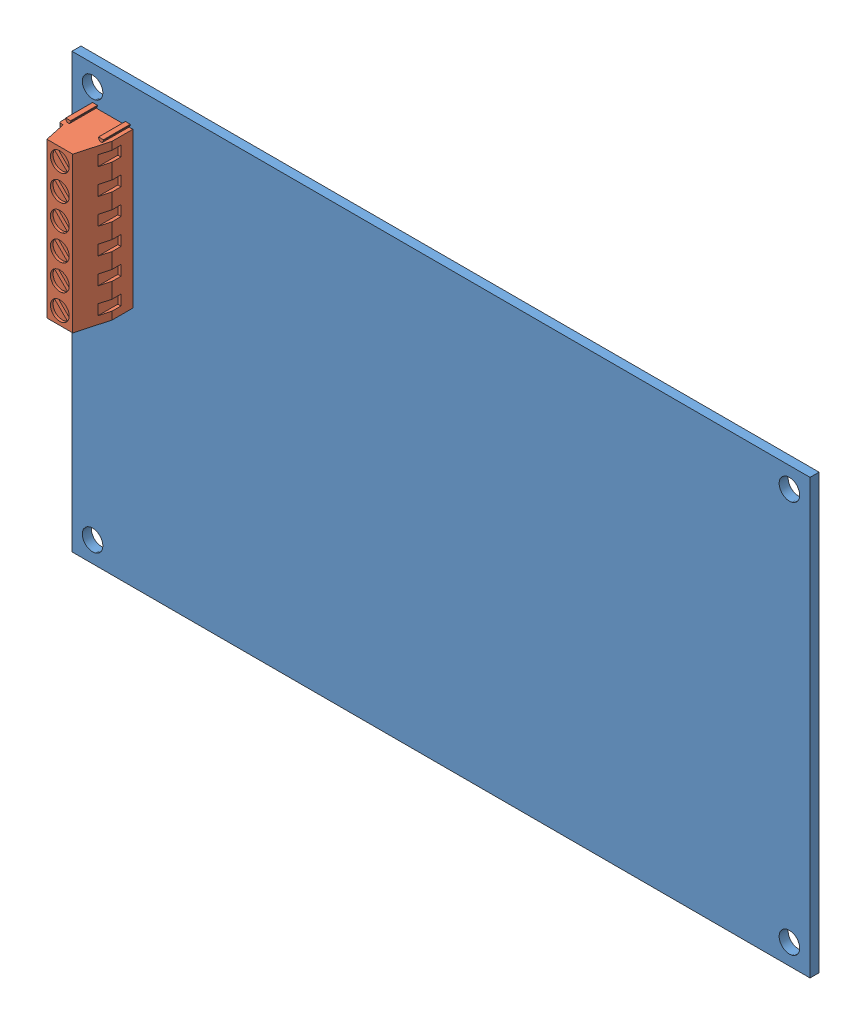
SolidWorks assembly MKS Gen V1.4 3D Printer Board v17, configuration simple. Lengths in mm.
Overall size (143 84 13.8).
45 component instances, 88 part files, 0 mates.
Components (placement in the parent):
- MKS Gen V1.4 3D Printer Board v17-1: MKS Gen V1.4 3D Printer Board v17 [Default] at origin (suppressed, hidden)
- PCB Board-1: PCB Board [Default] at origin size (143 84 1.75)
- 6 pin terminal block v1-1: 6 pin terminal block v1 [Default] at (-59.7021 19.8 1.75) x (0 -1 0) z (-1 0 0) size (30.6 13.8 8.3)
- Power terminal block v1-1: Power terminal block v1 [Default] at (-64.9521 -0.2 1.75) x (0 1 0) z (1 0 0) (suppressed, hidden)
- Power terminal block v1 (1)-1: Power terminal block v1 (1) [Default] at (-64.95 -26.8 1.75) x (0 1 0) z (1 0 0) (suppressed, hidden)
- USB socket v1-1: USB socket v1 [Default] at (-36.3816 15.6625 6.4412) x (0 1 0) z (1 0 0) (suppressed, hidden)
- Header 2_54 Vertical 2x3 v2-1: Header 2_54 Vertical 2x3 v2 [Default] at (-21.93 -38.73 1.75) x (1 0 0) z (0 -1 0) (suppressed, hidden)
- Header 2_54 Vertical 2x3 v2 (1)-1: Header 2_54 Vertical 2x3 v2 (1) [Default] at (-9.31 -38.73 1.75) x (1 0 0) z (0 -1 0) (suppressed, hidden)
- Header 2_54 Vertical 2x3 v2 (2)-1: Header 2_54 Vertical 2x3 v2 (2) [Default] at (5.21 -33.65 1.754) x (0 -1 0) z (-1 0 0) (suppressed, hidden)
- Header 2_54 Vertical 2x3 v2 (3)-1: Header 2_54 Vertical 2x3 v2 (3) [Default] at (10.29 -33.65 1.754) x (0 -1 0) z (-1 0 0) (suppressed, hidden)
- Header 2_54 Vertical 2x4 v1-1: Header 2_54 Vertical 2x4 v1 [Default] at (20.97 -38.73 1.754) x (1 0 0) z (0 -1 0) (suppressed, hidden)
- Header 2_54 Vertical 2x5 v1-1: Header 2_54 Vertical 2x5 v1 [Default] at (36.73 -38.73 1.754) x (1 0 0) z (0 -1 0) (suppressed, hidden)
- Header 2_54 Vertical 2x4 v1 (1)-1: Header 2_54 Vertical 2x4 v1 (1) [Default] at (55.13 -38.73 1.754) x (1 0 0) z (0 -1 0) (suppressed, hidden)
- 10 pin male socket v2-1: 10 pin male socket v2 [Default] at (90.0901 7.3406 1.75) x (0 1 0) z (1 0 0) (suppressed, hidden)
- 10 pin male socket v2 (1)-1: 10 pin male socket v2 (1) [Default] at (90.0901 28.9906 1.75) x (0 1 0) z (1 0 0) (suppressed, hidden)
- JST XH 3 Green v1-1: JST XH 3 Green v1 [Default] at (52.925 4.55 1.75) x (0 -1 0) z (-1 0 0) (suppressed, hidden)
- JST XH 3 Green v1 (1)-1: JST XH 3 Green v1 (1) [Default] at (46.175 4.55 1.75) x (0 -1 0) z (-1 0 0) (suppressed, hidden)
- JST XH 3 Blue v1-1: JST XH 3 Blue v1 [Default] at (39.425 4.55 1.75) x (0 -1 0) z (-1 0 0) (suppressed, hidden)
- JST XH 3 Blue v1 (1)-1: JST XH 3 Blue v1 (1) [Default] at (32.675 4.55 1.75) x (0 -1 0) z (-1 0 0) (suppressed, hidden)
- JST XH 3 Red v1-1: JST XH 3 Red v1 [Default] at (25.925 4.55 1.75) x (0 -1 0) z (-1 0 0) (suppressed, hidden)
- JST XH 3 Red v1 (1)-1: JST XH 3 Red v1 (1) [Default] at (19.175 4.55 1.75) x (0 -1 0) z (-1 0 0) (suppressed, hidden)
- JST XH 2 Black v1-1: JST XH 2 Black v1 [Default] at (52.1 -5.875 1.75) x (1 0 0) z (0 -1 0) (suppressed, hidden)
- JST XH 2 White v1-1: JST XH 2 White v1 [Default] at (52.1 -12.625 1.75) x (1 0 0) z (0 -1 0) (suppressed, hidden)
- JST XH 2 Purple v1-1: JST XH 2 Purple v1 [Default] at (52.1 -19.375 1.75) x (1 0 0) z (0 -1 0) (suppressed, hidden)
- JST XH 4 Purple v1-1: JST XH 4 Purple v1 [Default] at (57.4 37.625 1.75) x (1 0 0) z (0 -1 0) (suppressed, hidden)
- JST XH 4 Black v1-1: JST XH 4 Black v1 [Default] at (35.2 37.625 1.75) x (1 0 0) z (0 -1 0) (suppressed, hidden)
- JST XH 4 Green v1-1: JST XH 4 Green v1 [Default] at (13 37.625 1.75) x (1 0 0) z (0 -1 0) (suppressed, hidden)
- JST XH 4 Blue v1-1: JST XH 4 Blue v1 [Default] at (-9.2 37.625 1.75) x (1 0 0) z (0 -1 0) (suppressed, hidden)
- JST XH 4 Red v1-1: JST XH 4 Red v1 [Default] at (-31.4 37.625 1.75) x (1 0 0) z (0 -1 0) (suppressed, hidden)
- PIN HEADER FEMALE 8 - BLACK v4-1: PIN HEADER FEMALE 8 - BLACK v4 [Default] at (48.45 31.43 1.75) x (1 0 0) z (0 -1 0) (suppressed, hidden)
- PIN HEADER FEMALE 8 - GREEN v2-1: PIN HEADER FEMALE 8 - GREEN v2 [Default] at (48.45 19.08 1.75) x (1 0 0) z (0 -1 0) (suppressed, hidden)
- PIN HEADER FEMALE 8 - BLACK v4 (1)-1: PIN HEADER FEMALE 8 - BLACK v4 (1) [Default] at (26.63 31.43 1.75) x (1 0 0) z (0 -1 0) (suppressed, hidden)
- PIN HEADER FEMALE 8 - BLACK v4 (2)-1: PIN HEADER FEMALE 8 - BLACK v4 (2) [Default] at (4.81 31.43 1.75) x (1 0 0) z (0 -1 0) (suppressed, hidden)
- PIN HEADER FEMALE 8 - BLACK v4 (3)-1: PIN HEADER FEMALE 8 - BLACK v4 (3) [Default] at (-17.01 31.43 1.75) x (1 0 0) z (0 -1 0) (suppressed, hidden)
- PIN HEADER FEMALE 8 - BLACK v4 (4)-1: PIN HEADER FEMALE 8 - BLACK v4 (4) [Default] at (-38.83 31.43 1.75) x (1 0 0) z (0 -1 0) (suppressed, hidden)
- PIN HEADER FEMALE 8 - GREEN v2 (1)-1: PIN HEADER FEMALE 8 - GREEN v2 (1) [Default] at (26.63 19.08 1.75) x (1 0 0) z (0 -1 0) (suppressed, hidden)
- PIN HEADER FEMALE 8 - GREEN v2 (2)-1: PIN HEADER FEMALE 8 - GREEN v2 (2) [Default] at (4.81 19.08 1.75) x (1 0 0) z (0 -1 0) (suppressed, hidden)
- PIN HEADER FEMALE 8 - GREEN v2 (3)-1: PIN HEADER FEMALE 8 - GREEN v2 (3) [Default] at (-17.01 19.08 1.75) x (1 0 0) z (0 -1 0) (suppressed, hidden)
- PIN HEADER FEMALE 8 - GREEN v2 (4)-1: PIN HEADER FEMALE 8 - GREEN v2 (4) [Default] at (-38.83 19.08 1.75) x (1 0 0) z (0 -1 0) (suppressed, hidden)
- Header 2_54 Vertical 2x3 v2 (4)-1: Header 2_54 Vertical 2x3 v2 (4) [Default] at (-17.69 -13.238 1.75) x (0 1 0) z (1 0 0) (suppressed, hidden)
- User Library-Header 4 Vertical v1-1: User Library-Header 4 Vertical v1 [Default] at (53.8464 13.625 1.75) x (1 0 0) z (0 -1 0) (suppressed, hidden)
- User Library-Header 4 Vertical v1 (1)-1: User Library-Header 4 Vertical v1 (1) [Default] at (31.6464 13.625 1.75) x (1 0 0) z (0 -1 0) (suppressed, hidden)
- User Library-Header 4 Vertical v1 (2)-1: User Library-Header 4 Vertical v1 (2) [Default] at (9.4464 13.625 1.75) x (1 0 0) z (0 -1 0) (suppressed, hidden)
- User Library-Header 4 Vertical v1 (3)-1: User Library-Header 4 Vertical v1 (3) [Default] at (-12.7536 13.625 1.75) x (1 0 0) z (0 -1 0) (suppressed, hidden)
- User Library-Header 4 Vertical v1 (4)-1: User Library-Header 4 Vertical v1 (4) [Default] at (-34.9536 13.625 1.75) x (1 0 0) z (0 -1 0) (suppressed, hidden)
